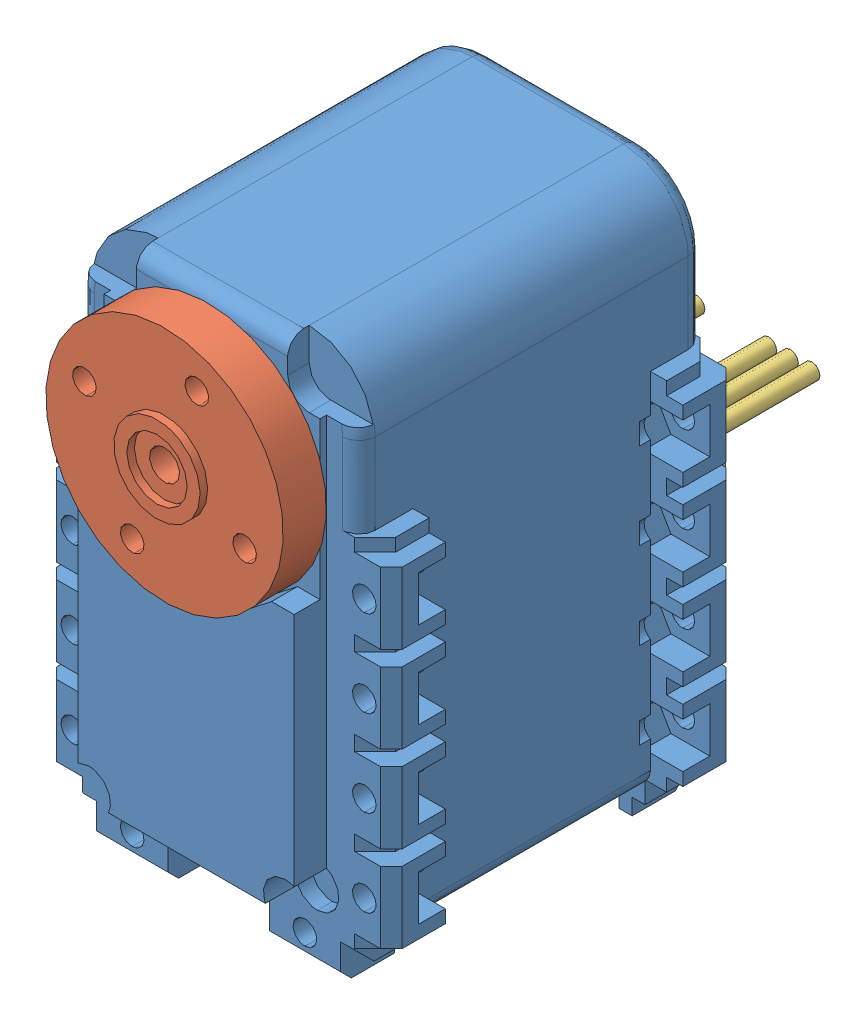
SolidWorks assembly servomoteur_ax-12, configuration Default. Lengths in mm.
Overall size (32 52.82 53.4).
4 component instances, 3 part files, 8 mates.
Components (placement in the parent):
- AX-12_modif-1: AX-12_modif [Défaut] at (-2.6768 21.8769 -4.3025) size (32 50.06 38.01)
- attache_ax-12-1: attache_ax-12 [Default] at (-2.6789 21.8765 12.6975) x (0.374116 0.927382 0) z (0 0 1) size (22 22 4.7)
- connecteur_AX-12-1: connecteur_AX-12 [Default] at (6.5732 8.6769 -17.5025) x (-1 0 0) z (0 -1 0) size (8 18.5 4)
- connecteur_AX-12-2: connecteur_AX-12 [Default] at (-4.0768 8.6769 -17.5025) x (-1 0 0) z (0 -1 0) size (8 18.5 4)
Mates (geometry in assembly coordinates):
- Coïncidente1: coincident anti-aligned: plane of AX-12_modif-1 through (8.7632 10.4369 12.6975) normal (0 0 1); plane of attache_ax-12-1 through (-2.6789 21.8765 12.6975) normal (0 0 -1)
- Tangent6: tangent: face of AX-12_modif-1; cylinder of attache_ax-12-1 through (-2.6789 21.8765 12.6965) axis (0 0 1) radius 1.4
- Coïncidente7: coincident anti-aligned: plane of AX-12_modif-1 through (7.7232 8.7632 -17.5025) normal (0 0 -1); plane of connecteur_AX-12-1 through (6.5732 8.6769 -17.5025) normal (0 0 1)
- Coïncidente8: coincident anti-aligned: plane of AX-12_modif-1 through (7.7232 8.7632 -17.5025) normal (0 0 -1); plane of connecteur_AX-12-2 through (-4.0768 8.6769 -17.5025) normal (0 0 1)
- Distance2: distance = 0.75 mm anti-aligned: plane of connecteur_AX-12-1 through (6.5732 5.6769 -21.5025) normal (1 0 0); plane of AX-12_modif-1 through (7.3232 11.0509 -17.4162) normal (-1 0 0)
- Coïncidente11: coincident anti-aligned: line of AX-12_modif-1 through (7.3232 8.6769 -17.5025) axis (-1 0 0); line of connecteur_AX-12-1 through (-1.4268 8.6769 -17.5025) axis (1 0 0)
- Coïncidente12: coincident aligned: line of AX-12_modif-1 through (-12.6768 8.6769 -17.5025) axis (1 0 0); line of connecteur_AX-12-2 through (-12.0768 8.6769 -17.5025) axis (1 0 0)
- Distance3: distance = 0.75 mm anti-aligned: plane of connecteur_AX-12-2 through (-4.0768 5.6769 -21.5025) normal (1 0 0); plane of AX-12_modif-1 through (-3.3268 11.0509 -20.3889) normal (-1 0 0)
